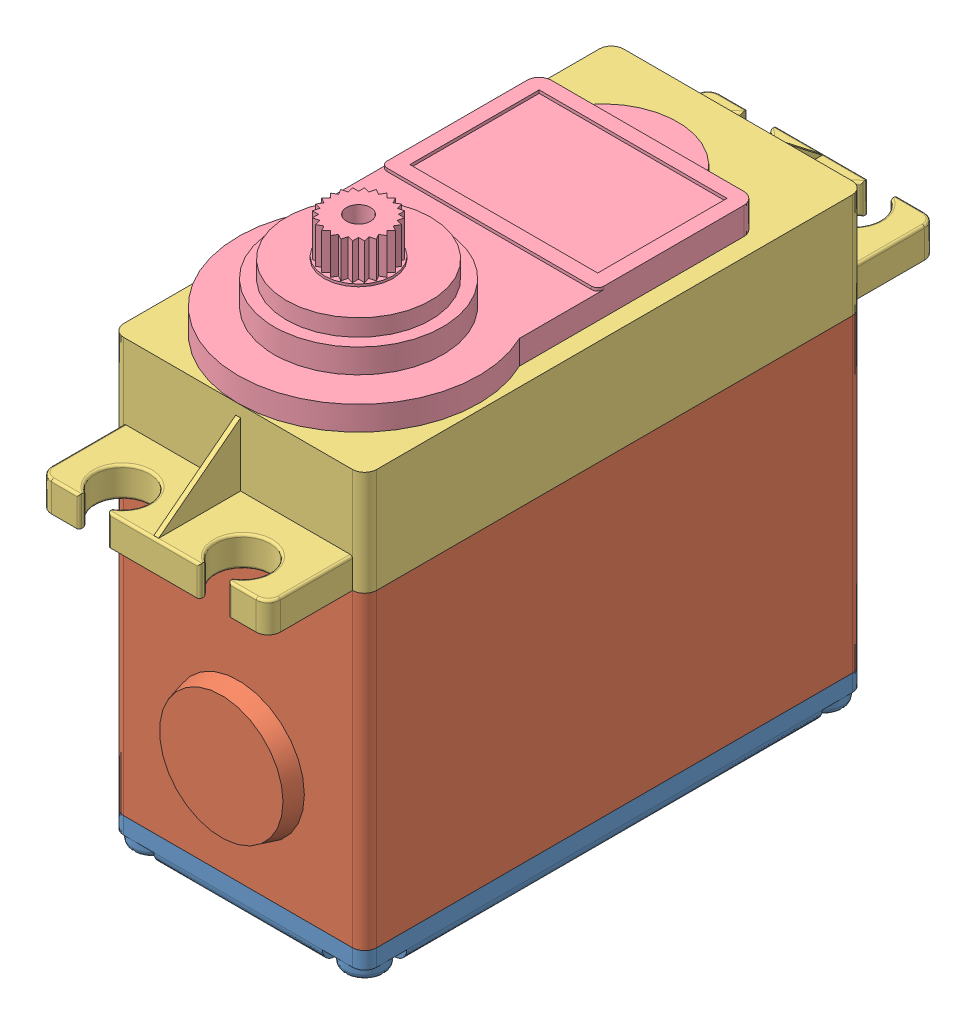
SolidWorks assembly 11886, configuration Default. Lengths in mm.
Overall size (21 45.43 55.5).
4 component instances, 4 part files, 6 mates.
Components (placement in the parent):
- 11886_bottom-1: 11886_bottom [Default] at (2.2223 -4.2785 0.9275) size (21 2.43 41.5)
- 11886_middle-1: 11886_middle [Default] at (2.2223 -1.8785 0.9275) size (21 25.7 42.9)
- 11886_upper-1: 11886_upper [Default] at (6.1473 23.8215 -5.3225) size (21 8.72 55.5)
- 11886_top-1: 11886_top [Default] at (2.2223 32.5215 0.7275) size (20 8.6 36.5)
Mates (geometry in assembly coordinates):
- Coincident1: coincident aligned: line of 11886_bottom-1 through (12.7223 -1.8785 20.6775) axis (0 0 -1); line of 11886_middle-1 through (12.7223 -1.8785 20.6775) axis (0 0 -1)
- Coincident2: coincident aligned: line of 11886_bottom-1 through (-7.2777 -1.8785 21.6775) axis (1 0 0); line of 11886_middle-1 through (-7.2777 -1.8785 21.6775) axis (1 0 0)
- Coincident3: coincident aligned: line of 11886_middle-1 through (12.7223 23.8215 20.6775) axis (0 0 -1); line of 11886_upper-1 through (12.7223 23.8215 20.6775) axis (0 0 -1)
- Concentric1: concentric aligned: cylinder of 11886_middle-1 through (11.7223 23.8215 20.6775) axis (0 -1 0) radius 1; cylinder of 11886_upper-1 through (11.7223 32.5215 20.6775) axis (0 -1 0) radius 1
- Coincident4: coincident anti-aligned: plane of 11886_upper-1 through (-8.2777 32.5215 -19.8225) normal (0 1 0); plane of 11886_top-1 through (-32.7773 32.5215 3.412) normal (0 -1 0)
- Coincident5: coincident: point of 11886_upper-1; unknown of 11886_top-1
